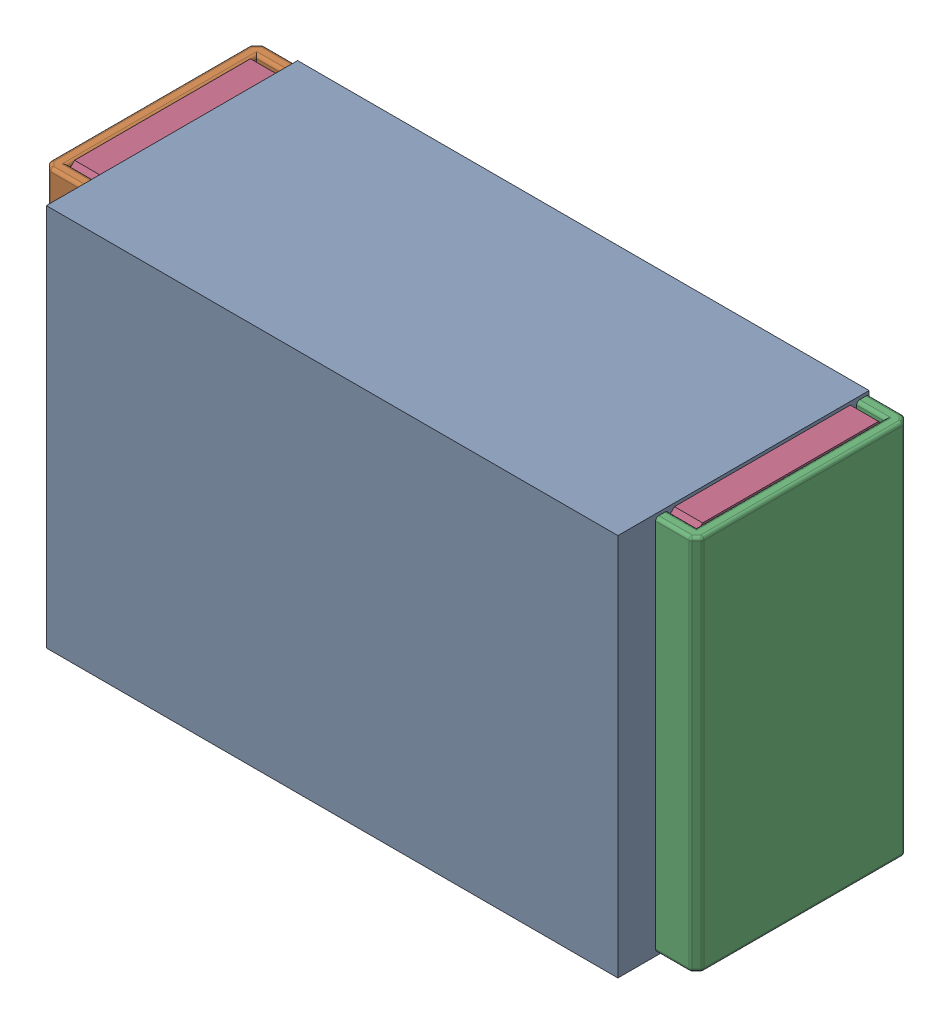
SolidWorks assembly R5, configuration Default. Lengths in mm.
Overall size (1.04 0.61 0.4).
3 component instances, 2 part files, 0 mates.
Components (placement in the parent):
- 1088880352-1: 1088880352 [Default] at (13.1 40.975 0) size (0.91 0.61 0.4)
  - Extruded-28-1: Extruded-28 [Default] at origin size (0.91 0.61 0.4)
- R0402-1: R0402 [Default] at (13.1 40.975 0) x (-1 0 0) z (0 1 0) size (1.04 0.34 0.6)
